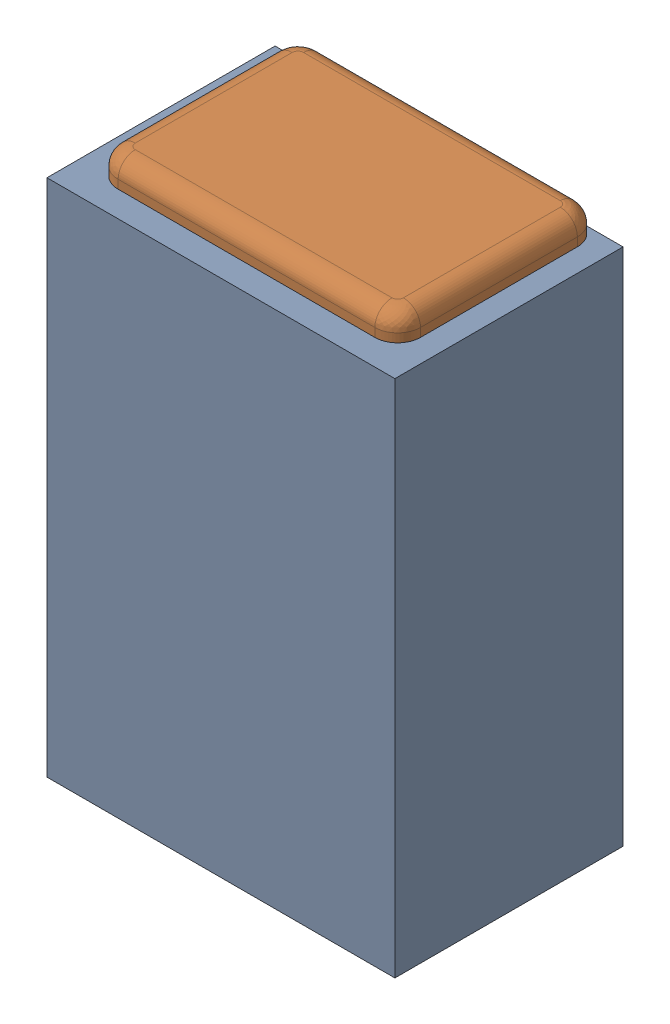
SolidWorks assembly C13, configuration Default. Lengths in mm.
Overall size (0.61 1 0.4).
3 component instances, 2 part files, 0 mates.
Components (placement in the parent):
- 1088881848-1: 1088881848 [Default] at (3.25 35.25 0) size (0.61 0.91 0.4)
  - Extruded-1-1: Extruded-1 [Default] at origin size (0.61 0.91 0.4)
- C0402-1: C0402 [Default] at (3.2499 35.2501 0) x (0 1 0) z (1 0 0) size (1 0.36 0.54)
